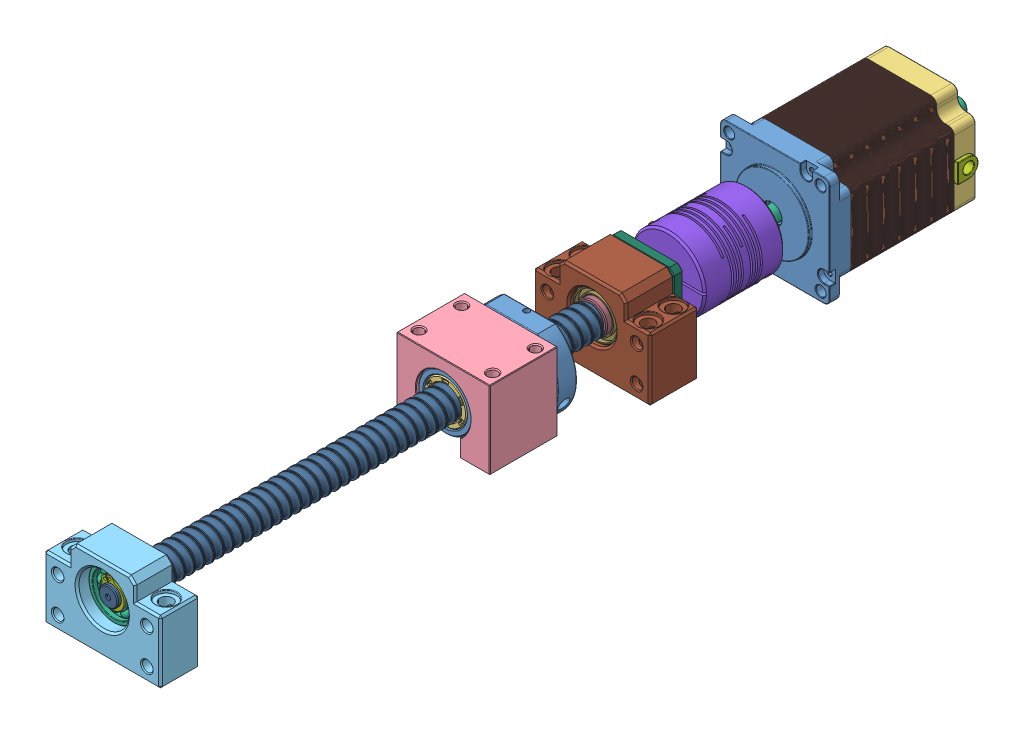
SolidWorks assembly CNC-Axis, configuration Default. Lengths in mm.
Overall size (60.2 56.6 442.3).
38 component instances, 25 part files, 13 mates.
Components (placement in the parent):
- 57BYGH311D-12-1: 57BYGH311D-12 [Default] at (4.6776 11.6572 13.1549) size (58.61 56.6 121)
  - 57BYGH311D-12-1-1: 57BYGH311D-12-1 [Default] at (-11.5747 12.4138 -2.3259) size (56.4 56.4 14.6)
  - 57BYGH311D-12-2-1: 57BYGH311D-12-2 [Default] at (-11.5747 12.4138 -55.5259) size (56.82 56.6 53.25)
  - 57BYGH311D-12-3-1: 57BYGH311D-12-3 [Default] at (-11.5747 12.4138 -55.5259) x (-1 0 0) z (0 0 -1) size (56.4 56.4 11)
  - 57BYGH311D-12-4-2: 57BYGH311D-12-4 [Default] at (-11.5747 12.4138 -70.0259) size (36 36 15.4)
  - 57BYGH311D-12-5-1: 57BYGH311D-12-5 [Default] at (-11.5747 12.4138 -70.5259) x (0.622515 0.782608 0) z (0 0 1) size (35.3 35.21 5)
  - 57BYGH311D-12-6-1: 57BYGH311D-12-6 [Default] at (-11.5747 12.4138 -86.8259) size (8 8 121)
  - 57BYGH311D-12-7-1: 57BYGH311D-12-7 [Default] at (15.4253 12.4138 -61.0259) x (1 0 0) z (0 1 0) size (6.2 10.5 12)
- MKS-C-2-C-150-08-10-1: MKS-C-2-C-150-08-10 [Default] at (0.4663 31.3512 52.2641) x (1 0 0) z (0 1 0) size (38.1 41.32 38.1)
  - MKS-C-2-C-150-08-10-1-1: MKS-C-2-C-150-08-10-1 [Default] at (-7.3634 16.4351 -7.2802) size (38.1 41.32 38.1)
  - socket head cap screw_am-3: socket head cap screw_am [B18.3.1M - 4 x 0.7 x 20 Hex SHCS -- 20NHX] at (3.6866 10.4351 -20.2802) x (-1 0 0) z (0 0.924225 0.381849) size (24 7 7)
  - socket head cap screw_am-4: socket head cap screw_am [B18.3.1M - 4 x 0.7 x 20 Hex SHCS -- 20NHX] at (-20.3634 -18.8649 -18.3302) x (0 0 1) z (-1 0 0) size (24 7 7)
- SCR1605-Z-1: SCR1605-Z [300mm] at (-6.8971 24.071 65.629) x (1 0 0) z (0 1 0) size (16.42 300 16.49)
- BK12-1: BK12 [Default] at (4.1309 15.874 103.1075) size (60 43 35.16)
  - BK12-1-1: BK12-1 [Default] at (-11.028 26.197 -11.9785) size (60 43 25)
  - BK12-2-5: BK12-2 [Default] at (-11.028 8.197 8.0215) size (24 24 3)
  - BK12-3-4: BK12-3 [Default] at (-11.028 8.197 8.0215) size (16 16 5.5)
  - 6001-Bearing-3: 6001-Bearing [Default] at (-11.028 8.197 0.0215) size (28 28 8)
  - 6001-Bearing-4: 6001-Bearing [Default] at (-11.028 8.197 -7.9785) size (28 28 8)
  - BK12-2-6: BK12-2 [Default] at (-11.028 8.197 -7.9785) x (-1 0 0) z (0 0 -1) size (24 24 3)
  - BK12-3-5: BK12-3 [Default] at (-11.028 8.197 -13.4785) size (16 16 5.5)
  - BK12-4-1: BK12-4 [Default] at (-11.028 8.197 -16.9785) size (34 34 9)
  - socket head cap screw_din-2: socket head cap screw_din [DIN 912 M3 x 8 --- 8N] at (-22.878 20.047 -16.9785) x (0 0 1) z (-1 0 0) size (11 5.5 5.5)
  - socket head cap screw_din-3: socket head cap screw_din [DIN 912 M3 x 8 --- 8N] at (-22.878 -3.653 -16.9785) x (0 0 1) z (-1 0 0) size (11 5.5 5.5)
  - socket head cap screw_din-4: socket head cap screw_din [DIN 912 M3 x 8 --- 8N] at (0.822 20.047 -16.9785) x (0 0 1) z (-1 0 0) size (11 5.5 5.5)
  - socket head cap screw_din-5: socket head cap screw_din [DIN 912 M3 x 8 --- 8N] at (0.822 -3.653 -16.9785) x (0 0 1) z (-1 0 0) size (11 5.5 5.5)
  - BK12-5-1: BK12-5 [Default] at (-11.028 8.197 -21.4785) size (19 19 8.53)
  - socket set screw cup point_din-18: socket set screw cup point_din [DIN 916 - M3 x 4-N] at (-3.3011 15.9239 -18.7785) x (-0.707107 -0.707107 0) z (-0.70706 0.70706 -0.011443) size (4 3 3)
  - socket set screw cup point_din-19: socket set screw cup point_din [DIN 916 - M3 x 4-N] at (-18.7549 15.9239 -18.7785) x (0.707107 -0.707107 0) z (0 0 1) size (4 3 3)
- SFU1605-1610-1: SFU1605-1610 [SFU1605-3] at (-0.5461 33.1978 166.2001) x (1 0 0) z (0 1 0) size (48 44 40)
  - SFU1605-1610-1-1: SFU1605-1610-1 [Default] at (-6.351 18.3668 -9.1268) size (48 44 40)
  - SFU1605-1610-3-1: SFU1605-1610-3 [Default] at (-6.351 8.3666 -9.1268) x (-0.92388 0 0.382683) z (-0.382683 0 -0.92388) size (22.05 10 22)
  - SFU1605-1610-2-1: SFU1605-1610-2 [Default] at (-6.351 -15.6332 -9.1268) x (1 0 0) z (0 0 -1) size (22 10 22)
- HD16-1: HD16 [Default] at (-6.8971 44.071 157.8333) size (48 40 35)
- BF12-1: BF12 [Default] at (5.903 20.0264 356.8513) size (60 43 20)
  - BF12-1-1: BF12-1 [Default] at (-12.8001 22.0446 -8.2224) size (60 43 20)
  - 6000-Bearing-1: 6000-Bearing [Default] at (-12.8001 4.0446 -2.2224) size (26 26 8)
- circlip for shafts normal_din-1: circlip for shafts normal_din [Circlip DIN 471 - 10 x 1] at (-6.8971 24.071 362.629) x (0.923728 0.383049 0) z (0 0 -1) size (12.16 14.7 1)
Mates (geometry in assembly coordinates):
- Concentric2: concentric anti-aligned: cylinder of 57BYGH311D-12-1/57BYGH311D-12-6-1 through (-6.8971 24.071 45.329) axis (0 0 1) radius 4; cylinder of MKS-C-2-C-150-08-10-1/MKS-C-2-C-150-08-10-1-1 through (-6.8971 24.071 35.829) axis (0 0 -1) radius 4
- Coincident1: coincident aligned: plane of 57BYGH311D-12-1/57BYGH311D-12-6-1 through (-10.8971 24.071 47.329) normal (0 0 1); plane of MKS-C-2-C-150-08-10-1/MKS-C-2-C-150-08-10-1-1 through (-10.8971 24.071 47.329) normal (0 0 1)
- Concentric3: concentric aligned: cylinder of MKS-C-2-C-150-08-10-1/MKS-C-2-C-150-08-10-1-1 through (-6.8971 24.071 35.829) axis (0 0 -1) radius 5; cylinder of SCR1605-Z-1 through (-6.8971 24.071 68.629) axis (0 0 -1) radius 5
- Coincident2: coincident aligned: plane of MKS-C-2-C-150-08-10-1/MKS-C-2-C-150-08-10-1-1 through (-13.8971 24.071 65.629) normal (0 0 -1); plane of SCR1605-Z-1 through (-11.8971 24.071 65.629) normal (0 0 -1)
- Coincident3: coincident anti-aligned: plane of SCR1605-Z-1 through (-14.8971 24.071 116.629) normal (0 0 -1); plane of BK12-1/BK12-3-4 through (-6.8971 24.071 116.629) normal (0 0 1)
- Concentric4: concentric aligned: cylinder of SCR1605-Z-1 through (-6.8971 24.071 68.629) axis (0 0 -1) radius 6; cylinder of BK12-1/6001-Bearing-4 through (-6.8971 24.071 103.129) axis (0 0 -1) radius 6
- Concentric5: concentric aligned: cylinder of SCR1605-Z-1 through (-6.8971 24.071 68.629) axis (0 0 -1) radius 8; cylinder of SFU1605-1610-1/SFU1605-1610-2-1 through (-6.8971 24.071 191.8333) axis (0 0 -1) radius 8
- Concentric6: concentric aligned: cylinder of SFU1605-1610-1/SFU1605-1610-1-1 through (-6.8971 24.071 147.8333) axis (0 0 -1) radius 14; cylinder of HD16-1 through (-6.8971 24.071 192.8333) axis (0 0 -1) radius 14.05
- Coincident4: coincident anti-aligned: plane of SFU1605-1610-1/SFU1605-1610-1-1 through (-6.8971 48.071 157.8333) normal (0 0 1); plane of HD16-1 through (-6.8971 24.071 157.8333) normal (0 0 -1)
- Coincident5: coincident anti-aligned: plane of SCR1605-Z-1 through (-14.8971 24.071 354.629) normal (0 0 1); plane of BF12-1/6000-Bearing-1 through (-6.8971 24.071 354.629) normal (0 0 -1)
- Concentric7: concentric aligned: cylinder of SCR1605-Z-1 through (-6.8971 24.071 68.629) axis (0 0 -1) radius 5; cylinder of BF12-1/6000-Bearing-1 through (-6.8971 24.071 362.629) axis (0 0 -1) radius 5
- Concentric8: concentric aligned: cylinder of SCR1605-Z-1 through (-6.8971 24.071 68.629) axis (0 0 -1) radius 4.8; cylinder of circlip for shafts normal_din-1 through (-6.8971 24.071 363.629) axis (0 0 -1) radius 4.8
- Coincident6: coincident anti-aligned: plane of SCR1605-Z-1 through (-11.8971 24.071 362.629) normal (0 0 1); plane of circlip for shafts normal_din-1 through (-6.8971 24.071 362.629) normal (0 0 -1)
